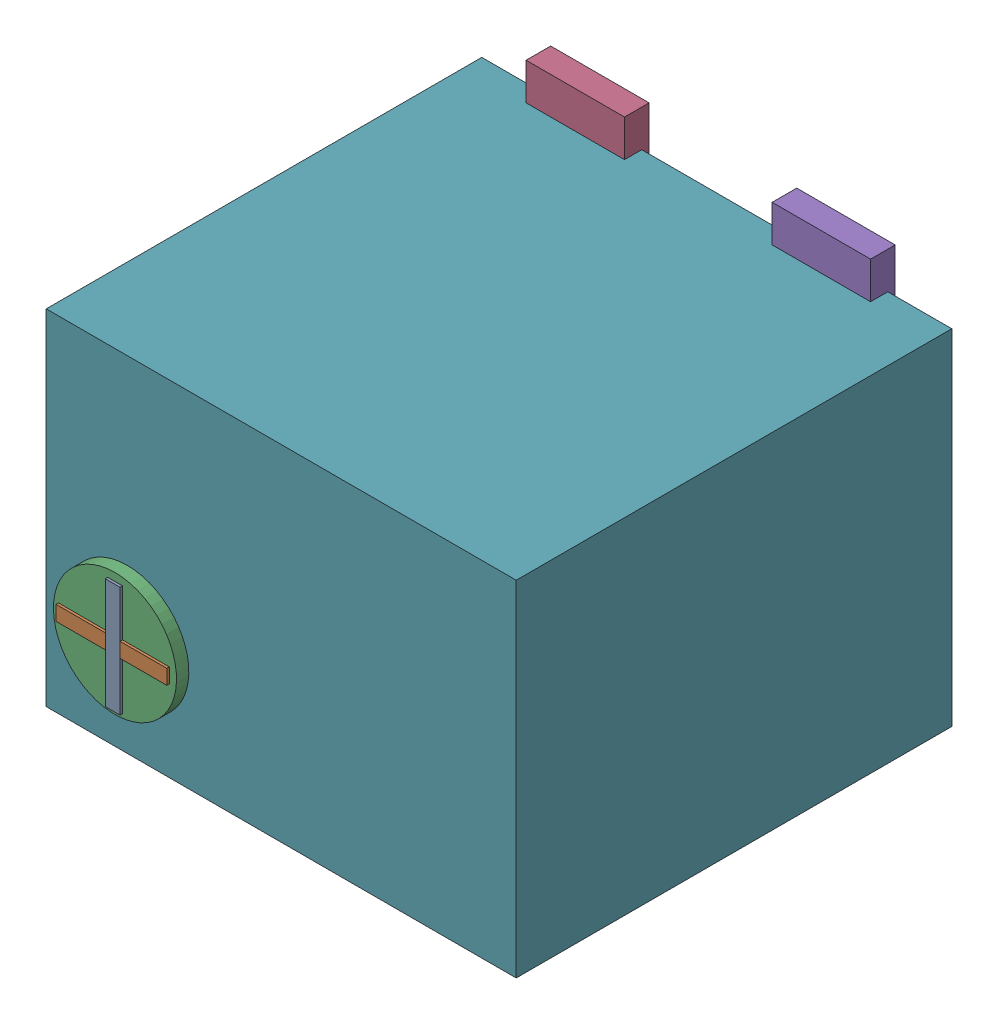
SolidWorks assembly TR2, configuration Default. Lengths in mm.
Overall size (4.85 4.32 4.72).
14 component instances, 6 part files, 0 mates.
Components (placement in the parent):
- 809727952-1: 809727952 [Default] at (59.7675 59.8297 4.699) size (0.15 1.14 0.03)
  - Extruded_5-1: Extruded_5 [Default] at origin size (0.15 1.14 0.03)
- 809728088-1: 809728088 [Default] at (59.7548 59.8424 4.699) size (1.14 0.15 0.03)
  - Extruded_6-1: Extruded_6 [Default] at origin size (1.14 0.15 0.03)
- 980253280-1: 980253280 [Default] at (59.7662 59.8474 4.572) x (0 -1 0) z (0 0 1) size (1.27 1.27 0.13)
  - Cylinder-1: Cylinder [Default] at origin size (1.27 1.27 0.13)
- 809728360-1: 809728360 [Default] at (60.0723 62.4586 0) size (1.02 0.56 0.25)
  - Extruded_7-1: Extruded_7 [Default] at origin size (1.02 0.56 0.25)
- 809728360-2: 809728360 [Default] at (62.6123 62.4586 0) size (1.02 0.56 0.25)
  - Extruded_7-1: Extruded_7 [Default] at origin size (1.02 0.56 0.25)
- 809728496-1: 809728496 [Default] at (61.3423 58.6994 0) size (1.68 0.56 0.25)
  - Extruded_8-1: Extruded_8 [Default] at origin size (1.68 0.56 0.25)
- 809728632-1: 809728632 [Default] at (61.355 60.579 0.0762) size (4.85 3.56 4.5)
  - Extruded_9-1: Extruded_9 [Default] at origin size (4.85 3.56 4.5)
